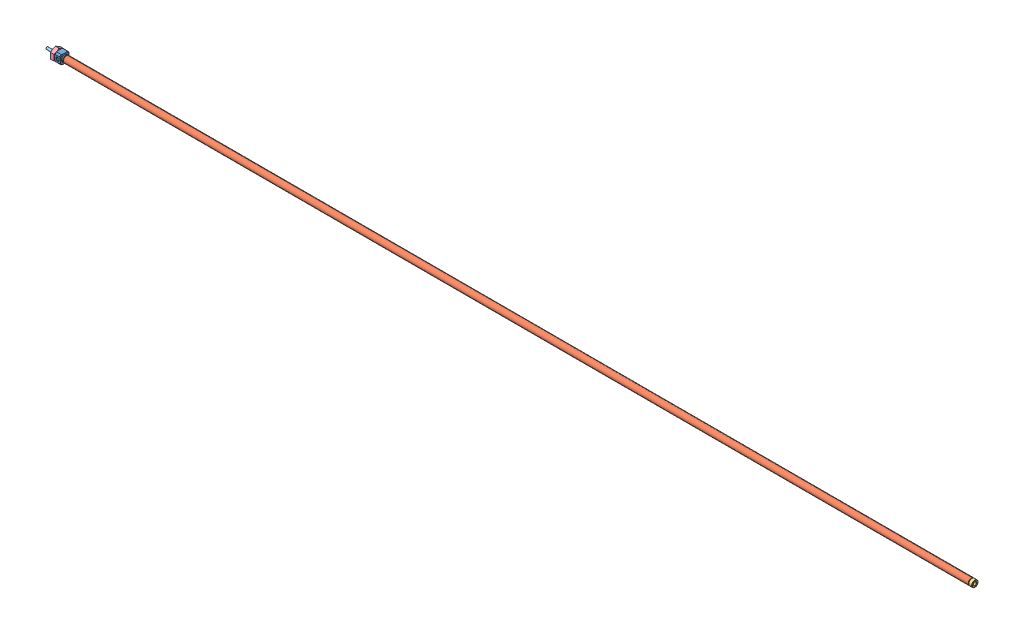
SolidWorks assembly Assem1, configuration Default. Lengths in mm.
Overall size (1321.31 16.42 14.22).
6 component instances, 6 part files, 14 mates.
Components (placement in the parent):
- 00750-D0000_0_dummy-1: 00750-D0000_0_dummy [Default] at origin
- 007R000-0_rod_guide-1: 007R000-0_rod_guide [Default] at origin size (21.46 12.7 12.7)
- 007R-50_740-1: 007R-50_740 [Default] at (17.9959 0 0) size (1289.76 9.12 9.12)
- 0070000_rear_head-1: 0070000_rear_head [Default] at (1303.3248 0 0) size (8.33 9.12 9.12)
- D-801-1: D-801 [Default] at (7.9248 0 0) x (0 0 -1) z (1 0 0) size (14.22 16.42 5.59)
- 00750-D0_rod-1: 00750-D0_rod [Default] at origin size (1312.98 8.06 8.06)
Mates (geometry in assembly coordinates):
- Distance2: distance = 0 mm aligned: plane of 007R000-0_rod_guide-1 through (0 0 0) normal (1 0 0); plane of 00750-D0000_0_dummy-1 through (0 0 0) normal (1 0 0)
- Coincident1: coincident aligned: line of 00750-D0000_0_dummy-1 through (80.9 0 0) axis (-1 0 0); line of 007R000-0_rod_guide-1 through (80.9 0 0) axis (-1 0 0)
- Angle3: planar angle = 0 rad aligned: plane of 007R000-0_rod_guide-1 through (0 0 0) normal (0 0 -1); plane of 00750-D0000_0_dummy-1 through (0 0 0) normal (0 0 -1)
- Distance4: distance = 0 mm aligned: plane of 007R-50_740-1 through (17.9959 0 0) normal (1 0 0); plane of 007R000-0_rod_guide-1 through (17.9959 0 0) normal (1 0 0)
- Coincident2: coincident aligned: line of 007R000-0_rod_guide-1 through (80.9 0 0) axis (-1 0 0); line of 007R-50_740-1 through (98.8959 0 0) axis (-1 0 0)
- Angle6: planar angle = 0 rad aligned: plane of 007R-50_740-1 through (17.9959 0 0) normal (0 0 -1); plane of 007R000-0_rod_guide-1 through (0 0 0) normal (0 0 -1)
- Distance6: distance = 0 mm aligned: plane of 0070000_rear_head-1 through (1306.7919 0 0) normal (1 0 0); plane of 007R-50_740-1 through (1306.7919 0 0) normal (1 0 0)
- Coincident3: coincident aligned: line of 007R-50_740-1 through (98.8959 0 0) axis (-1 0 0); line of 0070000_rear_head-1 through (1384.2248 0 0) axis (-1 0 0)
- Angle9: planar angle = 0 rad aligned: plane of 0070000_rear_head-1 through (1303.3248 0 0) normal (0 0 -1); plane of 007R-50_740-1 through (17.9959 0 0) normal (0 0 -1)
- Distance8: distance = 0 mm aligned: plane of D-801-1 through (7.9248 0 0) normal (1 0 0); plane of 007R000-0_rod_guide-1 through (7.9248 0 0) normal (1 0 0)
- Coincident4: coincident aligned: line of 007R000-0_rod_guide-1 through (80.9 0 0) axis (-1 0 0); line of D-801-1 through (88.8248 0 0) axis (-1 0 0)
- Angle12: planar angle = 0 rad aligned: plane of D-801-1 through (7.9248 0 0) normal (0 0 -1); plane of 007R000-0_rod_guide-1 through (0 0 0) normal (0 0 -1)
- LimitDistance2: limit distance = 0 mm aligned: plane of 00750-D0_rod-1 through (0 0 0) normal (1 0 0); plane of 007R000-0_rod_guide-1 through (0 0 0) normal (1 0 0)
- Coincident5: coincident aligned: line of 007R000-0_rod_guide-1 through (80.9 0 0) axis (-1 0 0); line of 00750-D0_rod-1 through (80.9 0 0) axis (-1 0 0)
